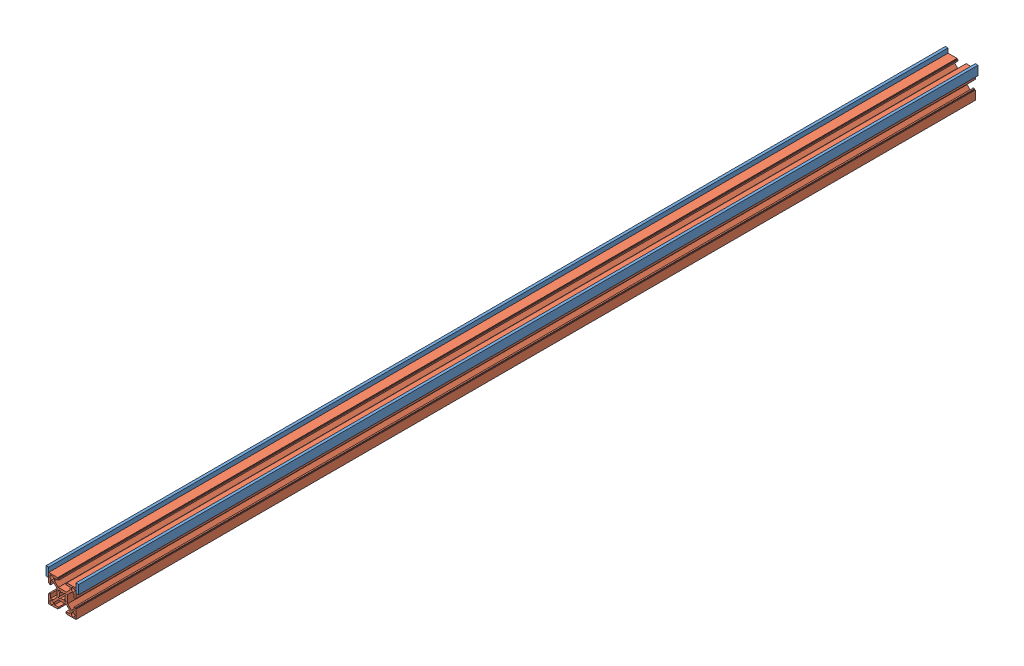
SolidWorks assembly Barricade track, configuration Default. Lengths in mm.
Overall size (36.29 35.29 1000).
3 component instances, 2 part files, 6 mates.
Components (placement in the parent):
- Rail guard-1: Rail guard [Default] at (318.4045 586.5736 1255.1753) size (3 10 1000)
- Track-1: Track [Default] at (321.4045 551.2884 1255.1753) size (30.29 30.29 1000)
- Rail guard-2: Rail guard [Default] at (351.6898 586.5736 1255.1753) size (3 10 1000)
Mates (geometry in assembly coordinates):
- Coincident1: coincident anti-aligned: plane of Rail guard-1 through (321.4045 586.5736 255.1753) normal (1 0 0); plane of Track-1 through (321.4045 581.5736 255.1753) normal (-1 0 0)
- Coincident2: coincident aligned: plane of Rail guard-1 through (318.4045 586.5736 1255.1753) normal (0 0 1); plane of Track-1 through (321.4045 551.2884 1255.1753) normal (0 0 1)
- Coincident3: coincident anti-aligned: plane of Track-1 through (351.6898 581.5736 255.1753) normal (1 0 0); plane of Rail guard-2 through (351.6898 586.5736 255.1753) normal (-1 0 0)
- Coincident4: coincident aligned: plane of Track-1 through (321.4045 551.2884 1255.1753) normal (0 0 1); plane of Rail guard-2 through (351.6898 586.5736 1255.1753) normal (0 0 1)
- Distance1: distance = 5 mm: line of Rail guard-1 through (321.4045 586.5736 255.1753) axis (0 0 1); line of Track-1 through (321.4045 581.5736 255.1753) axis (0 0 1)
- Distance2: distance = 5 mm: line of Rail guard-2 through (351.6898 586.5736 255.1753) axis (0 0 1); line of Track-1 through (351.6898 581.5736 255.1753) axis (0 0 1)
